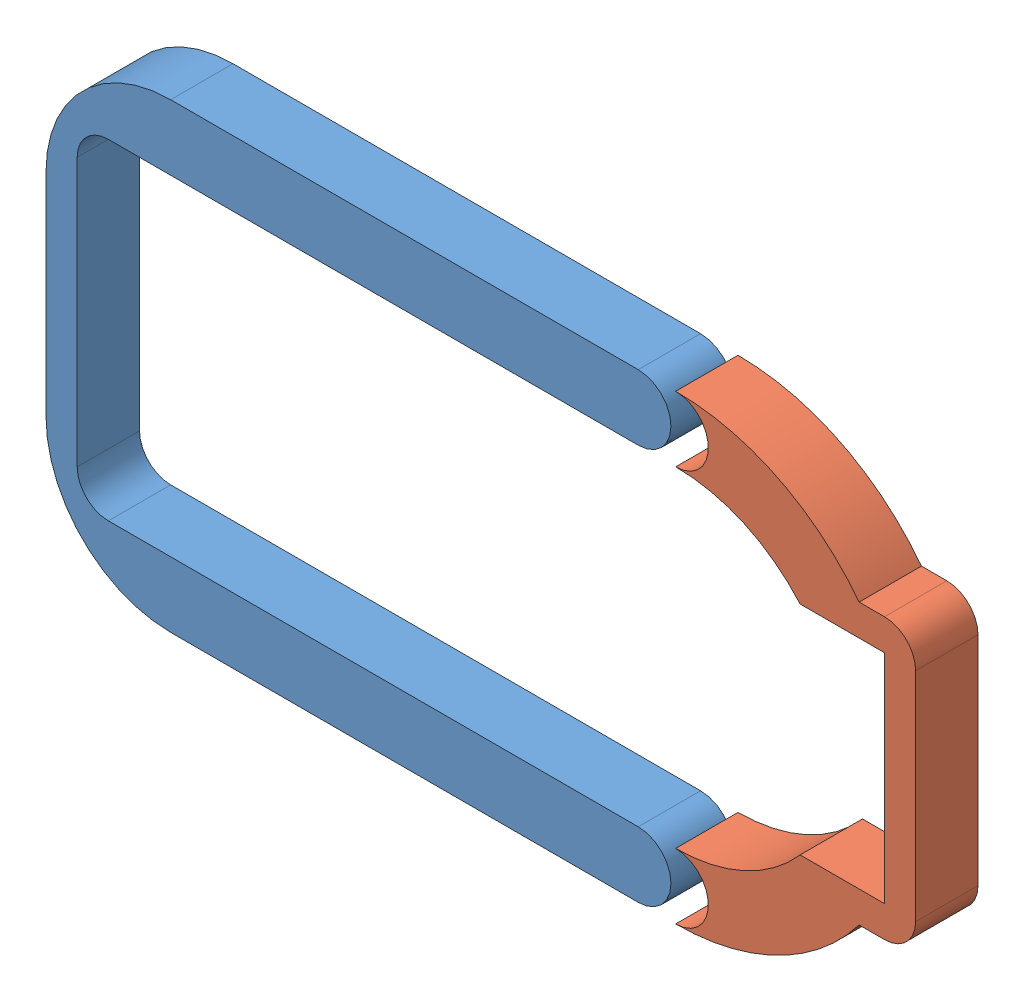
SolidWorks assembly MeadlleClamp, configuration По умолчанию. Lengths in mm.
Overall size (139.5 74 10).
2 component instances, 2 part files, 0 mates.
Components (placement in the parent):
- Boss-Extrude1-1: Boss-Extrude1 [По умолчанию] at origin size (100.25 74 10)
- Boss-Extrude2-1: Boss-Extrude2 [По умолчанию] at (6 0 0) size (38.5 74 10)
